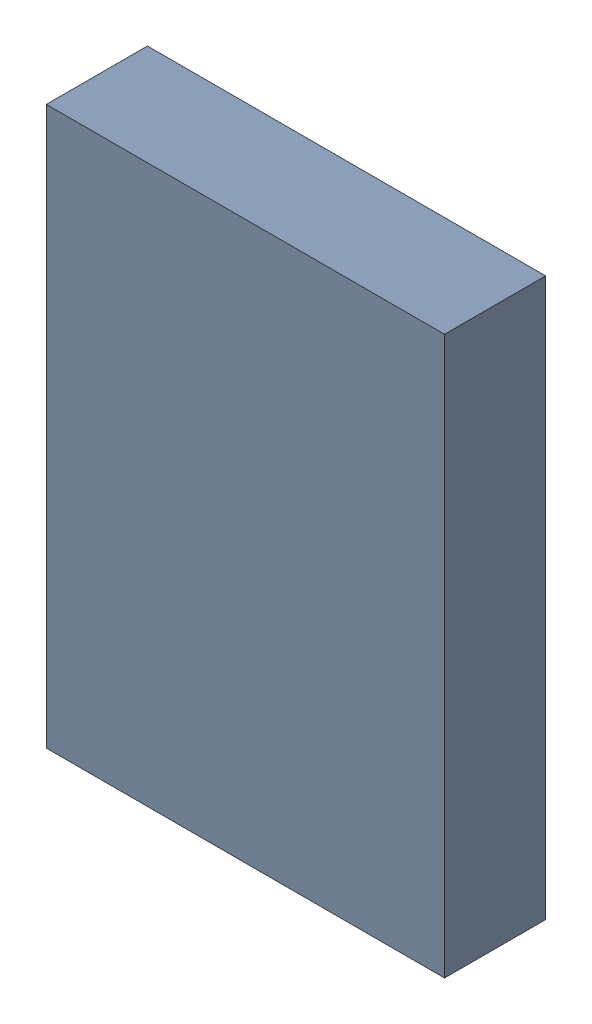
SolidWorks assembly R51, configuration Default. Lengths in mm.
Overall size (2.5 3.5 0.64).
2 component instances, 1 part files, 0 mates.
Components (placement in the parent):
- 870944960-1: 870944960 [Default] at (16.256 43.688 -2.2356) size (2.5 3.5 0.64)
  - Extruded_5-1: Extruded_5 [Default] at origin size (2.5 3.5 0.64)
